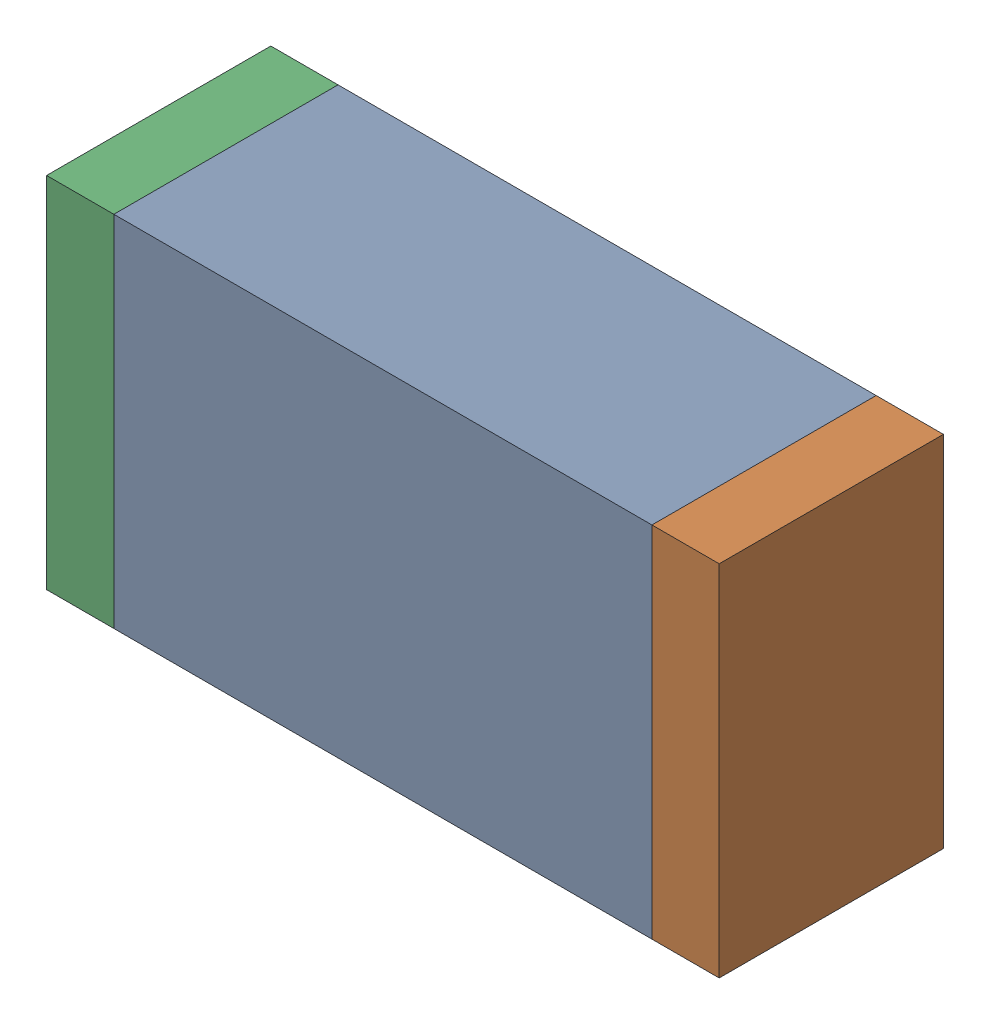
SolidWorks assembly C45, configuration Default. Lengths in mm.
Overall size (1.5 0.8 0.5).
6 component instances, 2 part files, 0 mates.
Components (placement in the parent):
- 836752368-1: 836752368 [Default] at (116 38.25 0) size (1.2 0.8 0.5)
  - Extruded-1: Extruded [Default] at origin size (1.2 0.8 0.5)
- 836752496-1: 836752496 [Default] at (116.675 38.25 0) size (0.15 0.8 0.5)
  - Extruded_2-1: Extruded_2 [Default] at origin size (0.15 0.8 0.5)
- 836752496-2: 836752496 [Default] at (115.325 38.25 0) size (0.15 0.8 0.5)
  - Extruded_2-1: Extruded_2 [Default] at origin size (0.15 0.8 0.5)
